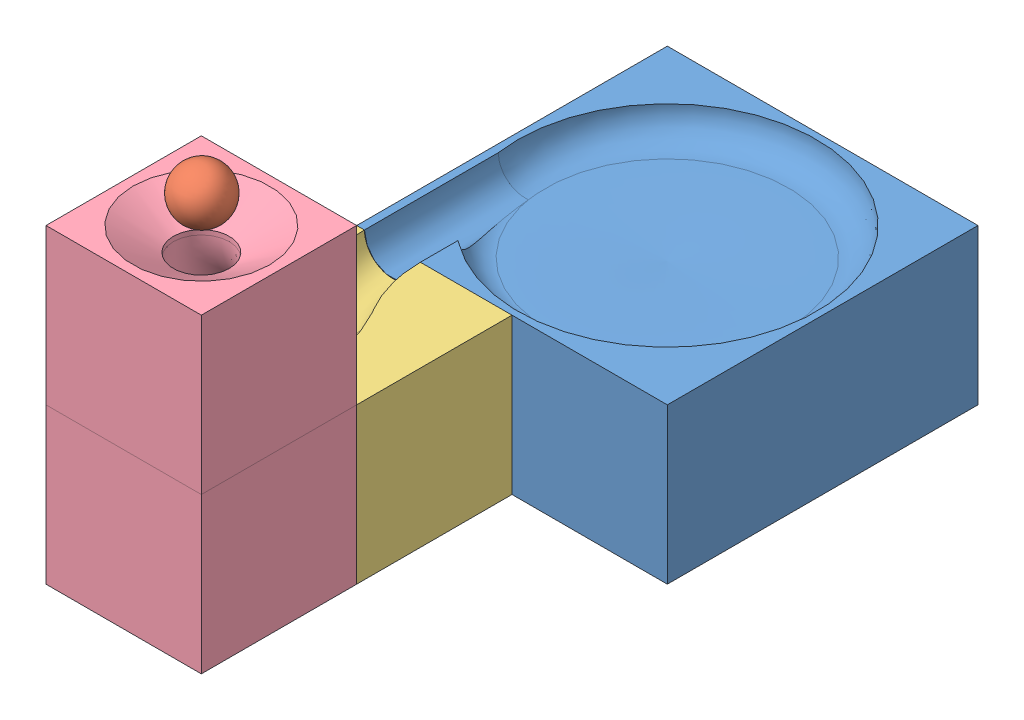
SolidWorks assembly marble run with Funnel, configuration Default. Lengths in mm.
Overall size (100 117.77 200).
5 component instances, 4 part files, 9 mates.
Components (placement in the parent):
- Teil1^marble run with Funnel-1: Teil1^marble run with Funnel [Standard] at origin size (100 52.96 100) (virtual)
- Kopie von Teil2^marble run with Funnel-1: Kopie von Teil2^marble run with Funnel [Standard] at (-24.7141 109.2663 125.1289) size (17 17 17) (virtual)
- Teil4^marble run with Funnel-1: Teil4^marble run with Funnel [Standard] at (-25 0 75) size (50 50 50.18) (virtual)
- Kopie von Teil4^marble run with Funnel-1: Kopie von Teil4^marble run with Funnel [Standard] at (-25 0 125) x (0 0 -1) z (1 0 0) size (50 50 50) (virtual)
- Kopie von Teil4^marble run with Funnel-2: Kopie von Teil4^marble run with Funnel [Standard] at (-25 50 125) x (0 0 -1) z (1 0 0) size (50 50 50) (virtual)
Mates (geometry in assembly coordinates):
- Deckungsgleich1: coincident aligned: plane of Teil1^Grafitationstrichter-1 through (-50 50 50) normal (-1 0 0); plane of Teil4^Grafitationstrichter-1 through (-50 50 100) normal (-1 0 0)
- Deckungsgleich2: coincident aligned: plane of Teil1^Grafitationstrichter-1 through (0 0 0) normal (0 -1 0); plane of Teil4^Grafitationstrichter-1 through (-25 0 75) normal (0 -1 0)
- Deckungsgleich3: coincident anti-aligned: plane of Teil1^Grafitationstrichter-1 through (-50 50 50) normal (0 0 1); plane of Teil4^Grafitationstrichter-1 through (-50 50 50) normal (0 0 -1)
- Deckungsgleich4: coincident anti-aligned: plane of Teil4^marble run with Funnel-1 through (-50 50 100) normal (0 0 1); plane of Kopie von Teil4^marble run with Funnel-1 through (0 50 100) normal (0 0 -1)
- Deckungsgleich5: coincident aligned: plane of Teil4^marble run with Funnel-1 through (-50 50 100) normal (-1 0 0); plane of Kopie von Teil4^marble run with Funnel-1 through (-50 50 150) normal (-1 0 0)
- Deckungsgleich6: coincident aligned: plane of Teil4^marble run with Funnel-1 through (-25 0 75) normal (0 -1 0); plane of Kopie von Teil4^marble run with Funnel-1 through (-25 0 125) normal (0 -1 0)
- Deckungsgleich7: coincident aligned: plane of Kopie von Teil4^marble run with Funnel-1 through (-50 50 150) normal (-1 0 0); plane of Kopie von Teil4^marble run with Funnel-2 through (-50 100 150) normal (-1 0 0)
- Deckungsgleich8: coincident aligned: plane of Kopie von Teil4^marble run with Funnel-1 through (0 50 150) normal (0 0 1); plane of Kopie von Teil4^marble run with Funnel-2 through (0 100 150) normal (0 0 1)
- Deckungsgleich9: coincident anti-aligned: plane of Kopie von Teil4^marble run with Funnel-1 through (-25 50 125) normal (0 1 0); plane of Kopie von Teil4^marble run with Funnel-2
